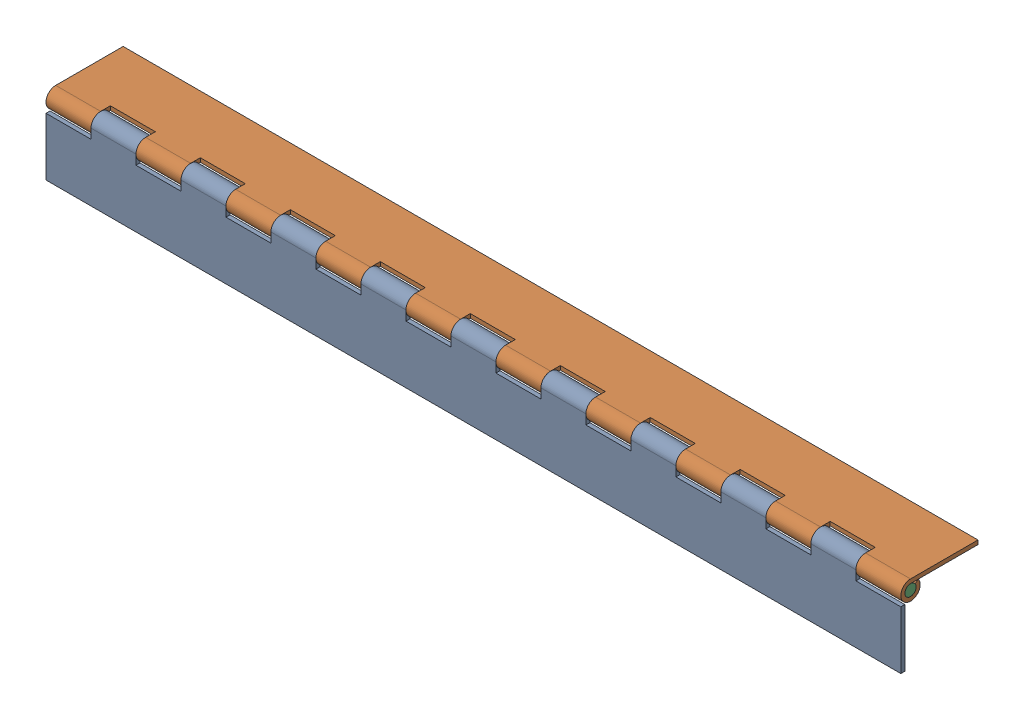
SolidWorks assembly FE-00004-03_ASM, configuration Default. Lengths in mm.
Overall size (482.6 43.56 43.56).
3 component instances, 3 part files, 0 mates.
Components (placement in the parent):
- FE-00004-03-A-1: FE-00004-03-A [Default] at origin size (482.6 43.56 10.92)
- FE-00004-03-B-1: FE-00004-03-B [Default] at (0 5.461 -5.461) x (-1 0 0) z (0 1 0) size (482.6 43.56 10.92)
- FE-00004-03-C-1: FE-00004-03-C [Default] at (0 0 -5.461) size (482.6 6.35 6.35)
